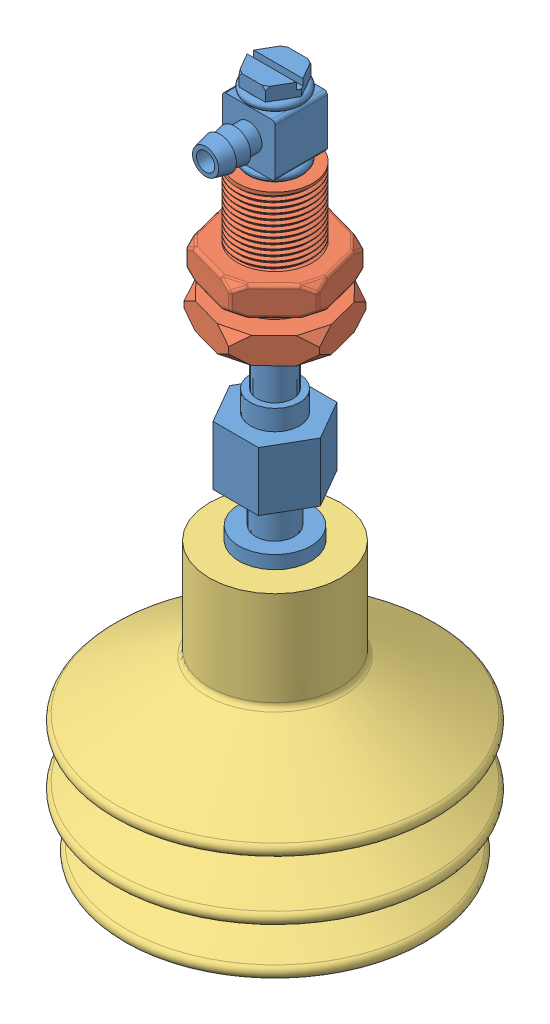
SolidWorks assembly 继手, configuration 默认. Lengths in mm.
Overall size (49.38 104.71 49.38).
3 component instances, 3 part files, 4 mates.
Components (placement in the parent):
- 继手1-1: 继手1 [默认] at origin size (13.86 62.71 16.6)
- 继手2-2: 继手2 [默认] at (0 29.1 0) x (0.962822 0 0.270137) z (-0.270137 0 0.962822) size (19.63 21.32 17)
- MP50吸盘-2: MP50吸盘 [默认] at (0 -15 0) size (49.38 42 49.38)
Mates (geometry in assembly coordinates):
- 同心1: concentric: circle of 继手1-1; circle of 继手2-2
- 重合2: coincident anti-aligned: plane of 继手1-1 through (0 50.1 0) normal (0 -1 0); plane of 继手2-2 through (0 50.1 0) normal (0 1 0)
- 同心2: concentric: circle of 继手1-1; circle of MP50吸盘-2
- 重合4: coincident anti-aligned: plane of 继手1-1 through (0 0 0) normal (0 -1 0); plane of MP50吸盘-2 through (0 0 0) normal (0 1 0)
